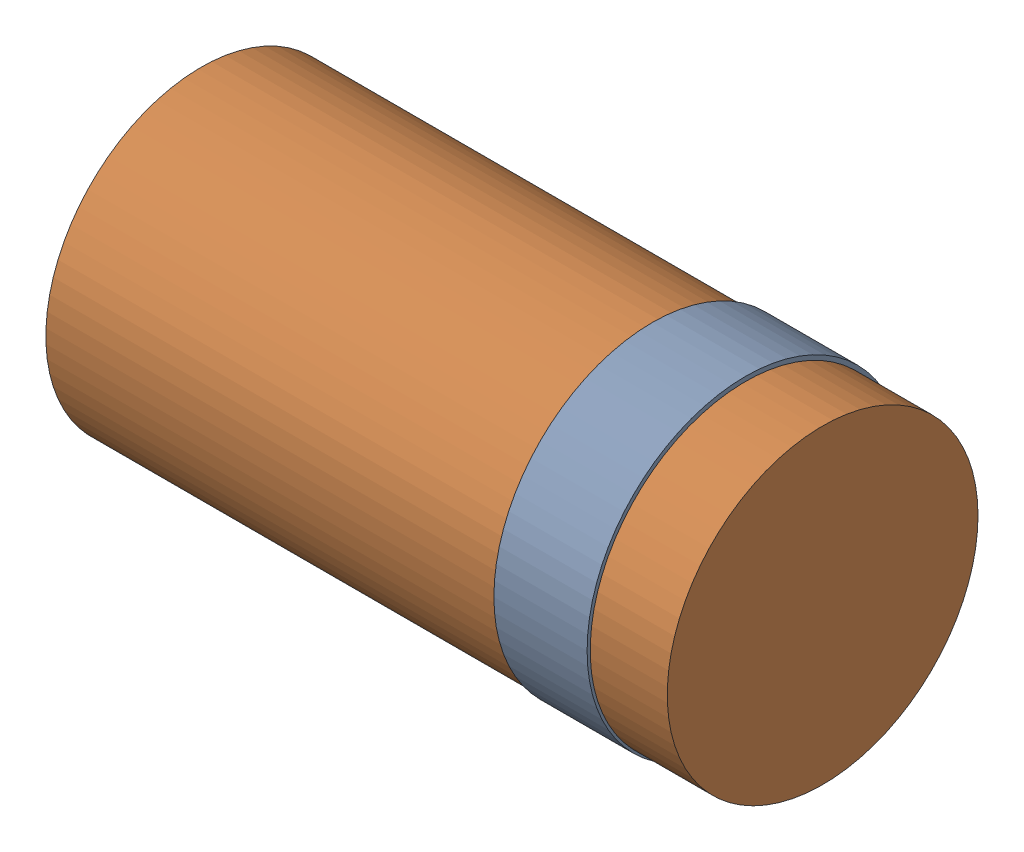
SolidWorks assembly D3Kanaloa_v2.0.0_Power, configuration Default. Lengths in mm.
Overall size (5.08 2.59 2.59).
4 component instances, 2 part files, 0 mates.
Components (placement in the parent):
- 425742296-1: 425742296 [Default] at (80.388 39.0935 -2.3724) x (0 0 1) z (1 0 0) size (2.59 2.59 0.76)
  - Cylinder-1: Cylinder [Default] at origin size (2.59 2.59 0.76)
- 425742776-1: 425742776 [Default] at (76.7 39.0825 -2.3724) x (0 0 1) z (1 0 0) size (2.54 2.54 5.08)
  - Cylinder_1-1: Cylinder_1 [Default] at origin size (2.54 2.54 5.08)
